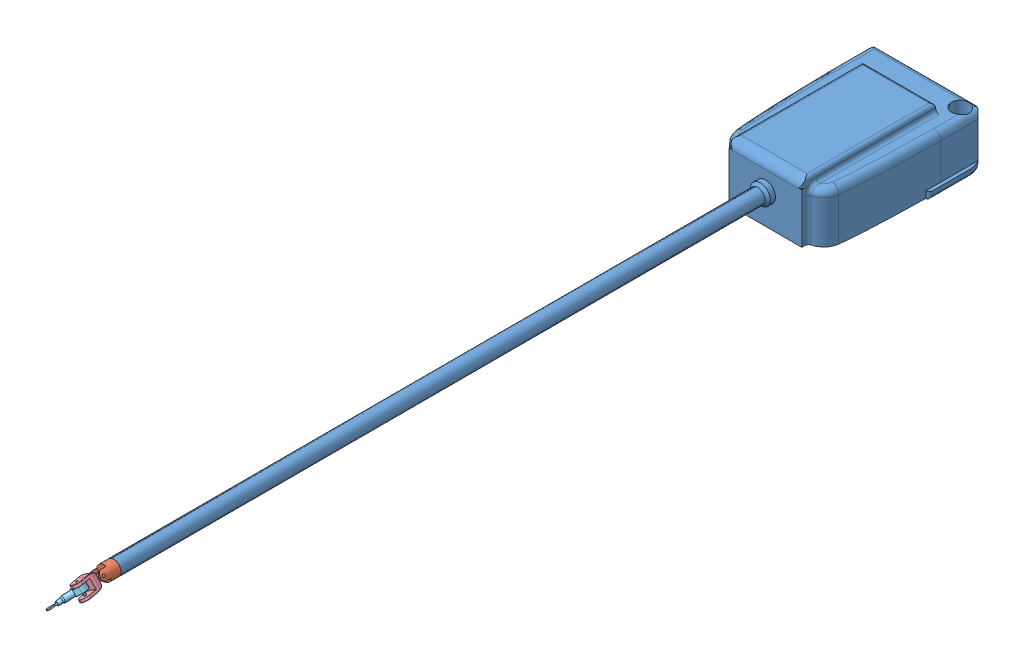
SolidWorks assembly Permanent_Cautery_Spatula, configuration Default. Lengths in mm.
Overall size (68.49 33 499.67).
6 component instances, 6 part files, 11 mates.
Components (placement in the parent):
- Tool_main-1: Tool_main [Default] at (-4.441 14.5005 -141.7985) size (68.49 33 464)
- Tool_Wrists_Link_1-1: Tool_Wrists_Link_1 [Default] at (-4.441 14.5005 225.0015) x (0.834571 0.5509 0) z (0 0 1) size (8.32 8.32 11)
- Tool_Wrists_Shaft_Link_1_2-1: Tool_Wrists_Shaft_Link_1_2 [Default] at (-7.6958 12.352 234.1015) x (-0.509156 0.771331 0.381849) z (0.834571 0.5509 0) size (1.3 1.3 8.02)
- Tool_Wristis_Permanent_cautery_Spatula_Link_2-1: Tool_Wristis_Permanent_cautery_Spatula_Link_2 [Default] at (25.2312 35.8919 195.0573) x (0.080286 -0.121627 0.989324) z (-0.545019 0.825661 0.145736) size (14.9 6.29 8.98)
- Tool_Wristis_Permanent_cautery_Spatula_Link_3-1: Tool_Wristis_Permanent_cautery_Spatula_Link_3 [Default] at (-5.1564 12.8419 247.3415) x (-0.799635 -0.459633 -0.38642) z (-0.252067 -0.327142 0.910736) size (6 3.3 19.84)
- Tool_Wristis_Permanent_cautery_Spatula_Shaft_Link_2_3-1: Tool_Wristis_Permanent_cautery_Spatula_Shaft_Link_2_3 [Default] at (-1.6248 10.1435 243.2431) x (-0.545019 0.825661 0.145736) z (-0.824375 -0.496042 -0.272668) size (8 1.3 1.3)
Mates (geometry in assembly coordinates):
- Coincident1: coincident anti-aligned: plane of Tool_main-1 through (-4.441 14.5005 225.0015) normal (0 0 1); plane of Tool_Wrists_Link_1-1 through (-4.441 14.5005 225.0015) normal (0 0 -1)
- Concentric1: concentric aligned: circle of Tool_main-1; circle of Tool_Wrists_Link_1-1
- Concentric2: concentric aligned: circle of Tool_Wrists_Link_1-1; cylinder of Tool_Wrists_Shaft_Link_1_2-1
- Distance1: distance = 0.7 mm anti-aligned: plane of Tool_Wrists_Shaft_Link_1_2-1 through (-7.6958 12.352 234.1015) normal (-0.834571 -0.5509 0); plane of Tool_Wrists_Link_1-1 through (-4.8198 9.2658 236.8589) normal (0.834571 0.5509 0)
- Concentric3: concentric anti-aligned: circle of Tool_Wrists_Link_1-1; circle of Tool_Wristis_Permanent_cautery_Spatula_Link_2-1
- Distance2: distance = 1.8 mm anti-aligned: plane of Tool_Wristis_Permanent_cautery_Spatula_Link_2-1 through (-4.2346 16.7292 232.5394) normal (0.834571 0.5509 0); plane of Tool_Wrists_Link_1-1 through (0.5214 12.7916 236.8589) normal (-0.834571 -0.5509 0)
- Concentric4: concentric anti-aligned: circle of Tool_Wristis_Permanent_cautery_Spatula_Link_2-1; cylinder of Tool_Wristis_Permanent_cautery_Spatula_Shaft_Link_2_3-1
- Coincident5: coincident aligned: plane of Tool_Wristis_Permanent_cautery_Spatula_Link_2-1 through (-5.8774 16.7674 244.7058) normal (-0.545019 0.825661 0.145736); plane of Tool_Wristis_Permanent_cautery_Spatula_Shaft_Link_2_3-1 through (-5.985 16.7488 244.409) normal (-0.545019 0.825661 0.145736)
- Concentric5: concentric anti-aligned: circle of Tool_Wristis_Permanent_cautery_Spatula_Link_3-1; circle of Tool_Wristis_Permanent_cautery_Spatula_Shaft_Link_2_3-1
- Coincident6: coincident anti-aligned: plane of Tool_Wristis_Permanent_cautery_Spatula_Link_2-1 through (-6.4155 11.7739 260.005) normal (0.545019 -0.825661 -0.145736); plane of Tool_Wristis_Permanent_cautery_Spatula_Link_3-1 through (-5.1186 16.2009 239.7744) normal (-0.545019 0.825661 0.145736)
- LimitAngle1: limit planar angle = 0.599424 rad aligned: plane of Tool_Wristis_Permanent_cautery_Spatula_Link_2-1 through (-5.8774 16.7674 244.7058) normal (-0.545019 0.825661 0.145736); plane of Tool_main-1 through (29.659 30.2505 -238.9985) normal (0 1 0)
